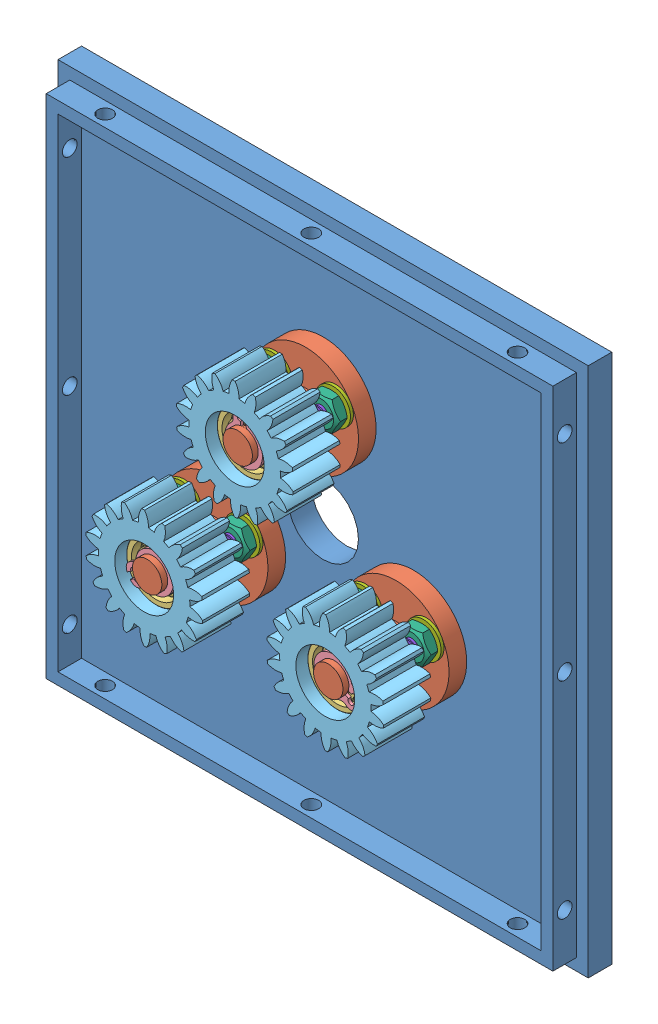
SolidWorks assembly 壳体-正, configuration 默认. Lengths in mm.
Overall size (90 90 21.5).
43 component instances, 8 part files, 9 mates.
Components (placement in the parent):
- 壳体-1: 壳体 [默认] at (44.9472 -6.7869 -4) size (90 90 8)
- 惰轮传动-1: 惰轮传动 [默认] at (41.1376 -52.1473 23.5095) x (0.48481 0.87462 0) z (0.87462 -0.48481 0) size (19.78 15 20)
  - 惰轮轴-1: 惰轮轴 [默认] at (41.2103 -20.5095 -0.913) size (18 14.5 18)
  - deep groove ball bearings gb-1: deep groove ball bearings gb [Rolling bearings 637-5 GB 276-94] at (41.2103 -12.5095 -0.913) x (0 -1 0) z (0.758451 0 -0.651731) size (4 10 10)
  - circlips for shaft--type a small gb-2: circlips for shaft--type a small gb [GB_CONNECTING_PIECE_RING_RRA 5] at (41.2103 -10.0095 -1.193) x (1 0 0) z (0 1 0) size (6.4 8.28 0.5)
  - spur gear_gb-3: spur gear_gb [GB - Spur gear 1M 18T 20PA 8FW ---S18A75H50L10.0N] at (41.2103 -8.5095 -0.913) x (0 -1 0) z (0 0 1) size (8 19.78 20)
- hex nuts, style 1-grades ab gb-1: hex nuts, style 1-grades ab gb [GB_FASTENER_NUT_SNAB1 M2.5-N] at (60.423 -21.6605 5.5) size (5.77 5 2)
- plain washers-n series-grade a gb-1: plain washers-n series-grade a gb [GB_FASTENER_WASHER_PWNA 2.5] at (65.4612 -12.5712 3.5) size (6 6 0.5)
- hexagon socket head cap screws gb-1: hexagon socket head cap screws gb [GB_FASTENER_SCREWS_HSHCS M2.5X10-N] at (60.423 -21.6605 -6.5) x (0 0 1) z (-0.600306 0.799771 0) size (12.5 4.5 4.5)
- hex nuts, style 1-grades ab gb-2: hex nuts, style 1-grades ab gb [GB_FASTENER_NUT_SNAB1 M2.5-N] at (65.4612 -12.5712 5.5) x (-0.5 0.866025 0) z (0 0 1) size (5.77 5 2)
- hex nuts, style 1-grades ab gb-3: hex nuts, style 1-grades ab gb [GB_FASTENER_NUT_SNAB1 M2.5-N] at (55.0705 -12.7525 5.5) x (-0.5 -0.866025 0) z (0 0 1) size (5.77 5 2)
- hexagon socket head cap screws gb-2: hexagon socket head cap screws gb [GB_FASTENER_SCREWS_HSHCS M2.5X10-N] at (65.4612 -12.5712 -6.5) x (0 0 1) z (-0.392469 -0.919765 0) size (12.5 4.5 4.5)
- hexagon socket head cap screws gb-3: hexagon socket head cap screws gb [GB_FASTENER_SCREWS_HSHCS M2.5X10-N] at (55.0705 -12.7525 -6.5) x (0 0 1) z (0.992775 0.119994 0) size (12.5 4.5 4.5)
- plain washers-n series-grade a gb-3: plain washers-n series-grade a gb [GB_FASTENER_WASHER_PWNA 2.5] at (55.0705 -12.7525 3.5) x (-0.5 0.866025 0) z (0 0 1) size (6 6 0.5)
- plain washers-n series-grade a gb-4: plain washers-n series-grade a gb [GB_FASTENER_WASHER_PWNA 2.5] at (60.423 -21.6605 3.5) x (-0.5 -0.866025 0) z (0 0 1) size (6 6 0.5)
- hex nuts, style 1-grades ab gb-4: hex nuts, style 1-grades ab gb [GB_FASTENER_NUT_SNAB1 M2.5-N] at (50.0902 14.0523 5.5) x (-0.5 0.866025 0) z (0 0 1) size (5.77 5 2)
- hex nuts, style 1-grades ab gb-5: hex nuts, style 1-grades ab gb [GB_FASTENER_NUT_SNAB1 M2.5-N] at (24.3283 -12.7525 5.5) x (-0.5 -0.866025 0) z (0 0 1) size (5.77 5 2)
- hexagon socket head cap screws gb-4: hexagon socket head cap screws gb [GB_FASTENER_SCREWS_HSHCS M2.5X10-N] at (50.0902 14.0523 -6.5) x (0 0 1) z (-0.392469 -0.919765 0) size (12.5 4.5 4.5)
- hexagon socket head cap screws gb-5: hexagon socket head cap screws gb [GB_FASTENER_SCREWS_HSHCS M2.5X10-N] at (24.3283 -12.7525 -6.5) x (0 0 1) z (0.992775 0.119994 0) size (12.5 4.5 4.5)
- plain washers-n series-grade a gb-5: plain washers-n series-grade a gb [GB_FASTENER_WASHER_PWNA 2.5] at (39.6994 13.871 3.5) x (-0.5 0.866025 0) z (0 0 1) size (6 6 0.5)
- plain washers-n series-grade a gb-6: plain washers-n series-grade a gb [GB_FASTENER_WASHER_PWNA 2.5] at (29.6808 -21.6605 3.5) x (-0.5 -0.866025 0) z (0 0 1) size (6 6 0.5)
- hex nuts, style 1-grades ab gb-6: hex nuts, style 1-grades ab gb [GB_FASTENER_NUT_SNAB1 M2.5-N] at (39.6994 13.871 5.5) x (-0.5 -0.866025 0) z (0 0 1) size (5.77 5 2)
- hex nuts, style 1-grades ab gb-7: hex nuts, style 1-grades ab gb [GB_FASTENER_NUT_SNAB1 M2.5-N] at (29.6808 -21.6605 5.5) size (5.77 5 2)
- hex nuts, style 1-grades ab gb-8: hex nuts, style 1-grades ab gb [GB_FASTENER_NUT_SNAB1 M2.5-N] at (45.0519 4.963 5.5) size (5.77 5 2)
- hex nuts, style 1-grades ab gb-9: hex nuts, style 1-grades ab gb [GB_FASTENER_NUT_SNAB1 M2.5-N] at (34.7191 -12.5712 5.5) x (-0.5 0.866025 0) z (0 0 1) size (5.77 5 2)
- hexagon socket head cap screws gb-6: hexagon socket head cap screws gb [GB_FASTENER_SCREWS_HSHCS M2.5X10-N] at (39.6994 13.871 -6.5) x (0 0 1) z (0.992775 0.119994 0) size (12.5 4.5 4.5)
- hexagon socket head cap screws gb-7: hexagon socket head cap screws gb [GB_FASTENER_SCREWS_HSHCS M2.5X10-N] at (29.6808 -21.6605 -6.5) x (0 0 1) z (-0.600306 0.799771 0) size (12.5 4.5 4.5)
- hexagon socket head cap screws gb-8: hexagon socket head cap screws gb [GB_FASTENER_SCREWS_HSHCS M2.5X10-N] at (45.0519 4.963 -6.5) x (0 0 1) z (-0.600306 0.799771 0) size (12.5 4.5 4.5)
- hexagon socket head cap screws gb-9: hexagon socket head cap screws gb [GB_FASTENER_SCREWS_HSHCS M2.5X10-N] at (34.7191 -12.5712 -6.5) x (0 0 1) z (-0.392469 -0.919765 0) size (12.5 4.5 4.5)
- plain washers-n series-grade a gb-7: plain washers-n series-grade a gb [GB_FASTENER_WASHER_PWNA 2.5] at (45.0519 4.963 3.5) x (-0.5 -0.866025 0) z (0 0 1) size (6 6 0.5)
- plain washers-n series-grade a gb-8: plain washers-n series-grade a gb [GB_FASTENER_WASHER_PWNA 2.5] at (34.7191 -12.5712 3.5) size (6 6 0.5)
- plain washers-n series-grade a gb-9: plain washers-n series-grade a gb [GB_FASTENER_WASHER_PWNA 2.5] at (50.0902 14.0523 3.5) size (6 6 0.5)
- plain washers-n series-grade a gb-10: plain washers-n series-grade a gb [GB_FASTENER_WASHER_PWNA 2.5] at (24.3283 -12.7525 3.5) x (-0.5 0.866025 0) z (0 0 1) size (6 6 0.5)
- 惰轮传动-2: 惰轮传动 [默认] at (86.1352 12.5942 23.5095) x (-0.999848 -0.017452 0) z (-0.017452 0.999848 0) size (19.78 15 20)
  - 惰轮轴-1: 惰轮轴 [默认] at (41.2103 -20.5095 -0.913) size (18 14.5 18)
  - deep groove ball bearings gb-1: deep groove ball bearings gb [Rolling bearings 637-5 GB 276-94] at (41.2103 -12.5095 -0.913) x (0 -1 0) z (0.758451 0 -0.651731) size (4 10 10)
  - circlips for shaft--type a small gb-2: circlips for shaft--type a small gb [GB_CONNECTING_PIECE_RING_RRA 5] at (41.2103 -10.0095 -1.193) x (1 0 0) z (0 1 0) size (6.4 8.28 0.5)
  - spur gear_gb-3: spur gear_gb [GB - Spur gear 1M 18T 20PA 8FW ---S18A75H50L10.0N] at (41.2103 -8.5095 -0.913) x (0 -1 0) z (0 0 1) size (8 19.78 20)
- 惰轮传动-3: 惰轮传动 [默认] at (7.5686 19.1925 23.5095) x (0.515038 -0.857167 0) z (-0.857167 -0.515038 0) size (19.78 15 20)
  - 惰轮轴-1: 惰轮轴 [默认] at (41.2103 -20.5095 -0.913) size (18 14.5 18)
  - deep groove ball bearings gb-1: deep groove ball bearings gb [Rolling bearings 637-5 GB 276-94] at (41.2103 -12.5095 -0.913) x (0 -1 0) z (0.758451 0 -0.651731) size (4 10 10)
  - circlips for shaft--type a small gb-2: circlips for shaft--type a small gb [GB_CONNECTING_PIECE_RING_RRA 5] at (41.2103 -10.0095 -1.193) x (1 0 0) z (0 1 0) size (6.4 8.28 0.5)
  - spur gear_gb-3: spur gear_gb [GB - Spur gear 1M 18T 20PA 8FW ---S18A75H50L10.0N] at (41.2103 -8.5095 -0.913) x (0 -1 0) z (0 0 1) size (8 19.78 20)
Mates (geometry in assembly coordinates):
- 同心1: concentric anti-aligned: cylinder of 壳体-1 through (55.0705 -12.7525 0) axis (0 0 -1) radius 1.25; cylinder of 惰轮传动-1/惰轮轴-1 through (55.0705 -12.7525 3) axis (0 0 1) radius 1.025
- 同心2: concentric anti-aligned: cylinder of 壳体-1 through (65.4612 -12.5712 0) axis (0 0 -1) radius 1.25; cylinder of 惰轮传动-1/惰轮轴-1 through (65.4612 -12.5712 3) axis (0 0 1) radius 1.025
- 重合1: coincident anti-aligned: plane of 壳体-1 through (44.9472 -6.7869 0) normal (0 0 1); plane of 惰轮传动-1/惰轮轴-1 through (60.3182 -15.6614 0) normal (0 0 -1)
- 同心41: concentric aligned: cylinder of 惰轮传动-1/惰轮轴-1 through (65.4612 -12.5712 3) axis (0 0 1) radius 1.025; cylinder of plain washers-n series-grade a gb-1 through (65.4612 -12.5712 3) axis (0 0 1) radius 1.35
- 重合31: coincident anti-aligned: plane of 惰轮传动-1/惰轮轴-1 through (60.3182 -15.6614 3) normal (0 0 1); plane of plain washers-n series-grade a gb-1 through (65.4612 -12.5712 3) normal (0 0 -1)
- 同心61: concentric aligned: cylinder of 壳体-1 through (60.423 -21.6605 0) axis (0 0 -1) radius 1.25; cylinder of hexagon socket head cap screws gb-1 through (60.423 -21.6605 6) axis (0 0 -1) radius 1.25
- 同心71: concentric anti-aligned: cylinder of hex nuts, style 1-grades ab gb-1 through (60.423 -21.6605 3.5) axis (0 0 1) radius 1.0065; cylinder of hexagon socket head cap screws gb-1 through (60.423 -21.6605 6) axis (0 0 -1) radius 1.25
- 重合51: coincident anti-aligned: plane of hex nuts, style 1-grades ab gb-1 through (63.3097 -21.6605 3.5) normal (0 0 -1); plane of plain washers-n series-grade a gb-1 through (65.4612 -12.5712 3.5) normal (0 0 1)
- 重合6: coincident anti-aligned: plane of 壳体-1 through (44.9472 -6.7869 -4) normal (0 0 -1); plane of hexagon socket head cap screws gb-1 through (60.423 -21.6605 -4) normal (0 0 1)
